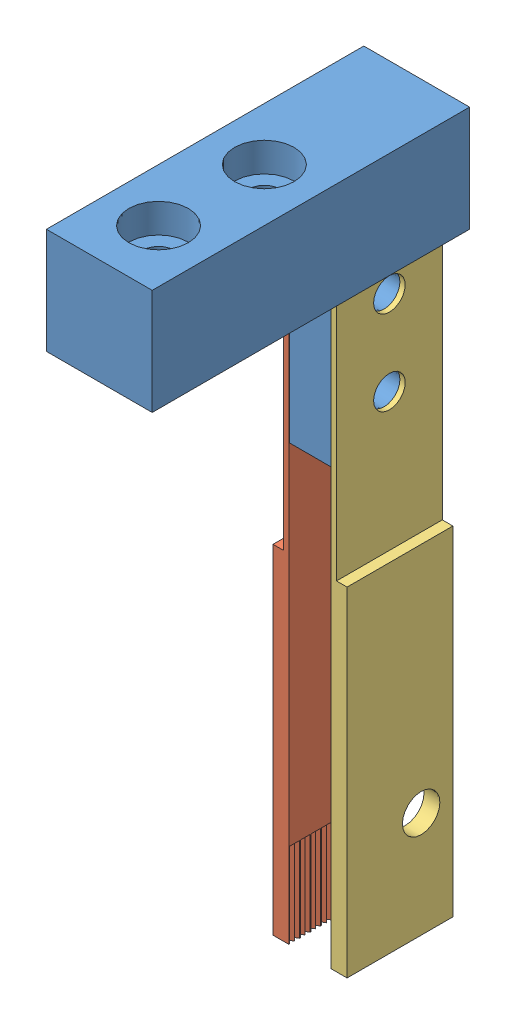
SolidWorks assembly Serrated grip assem, configuration Default. Lengths in mm.
Overall size (12.7 85.09 38.1).
3 component instances, 3 part files, 6 mates.
Components (placement in the parent):
- Serrated grip holder-1: Serrated grip holder [Default] at (4.6814 41.761 46.3313) size (12.7 33.02 38.1)
- Serrated grip left-1: Serrated grip left [Default] at (8.4914 -43.329 8.3333) x (0 1 0) z (0 0 1) size (72.39 1.91 12.7)
- Serrated grip right-1: Serrated grip right [Default] at (13.5714 -43.329 21.0333) x (0 1 0) z (0 0 -1) size (72.39 1.91 12.7)
Mates (geometry in assembly coordinates):
- Coincident1: coincident anti-aligned: plane of Serrated grip holder-1 through (8.4914 29.061 20.9313) normal (-1 0 0); plane of Serrated grip Left 1-1 through (8.4914 -43.329 8.3333) normal (1 0 0)
- Coincident2: coincident anti-aligned: plane of Serrated grip holder-1 through (13.5714 29.061 20.9313) normal (1 0 0); plane of Serrated grip right 1-1 through (13.5714 -43.329 21.0333) normal (-1 0 0)
- Coincident3: coincident anti-aligned: line of Serrated grip holder-1 through (8.4914 23.981 14.6833) axis (1 0 0); line of Serrated grip right 1-1 through (14.2064 23.981 14.6833) axis (-1 0 0)
- Coincident4: coincident anti-aligned: line of Serrated grip holder-1 through (8.4914 13.821 14.6833) axis (1 0 0); line of Serrated grip right 1-1 through (14.2064 13.821 14.6833) axis (-1 0 0)
- Coincident5: coincident aligned: line of Serrated grip holder-1 through (8.4914 23.981 14.6833) axis (1 0 0); line of Serrated grip Left 1-1 through (7.8564 23.981 14.6833) axis (1 0 0)
- Coincident6: coincident aligned: line of Serrated grip holder-1 through (8.4914 13.821 14.6833) axis (1 0 0); line of Serrated grip Left 1-1 through (7.8564 13.821 14.6833) axis (1 0 0)
